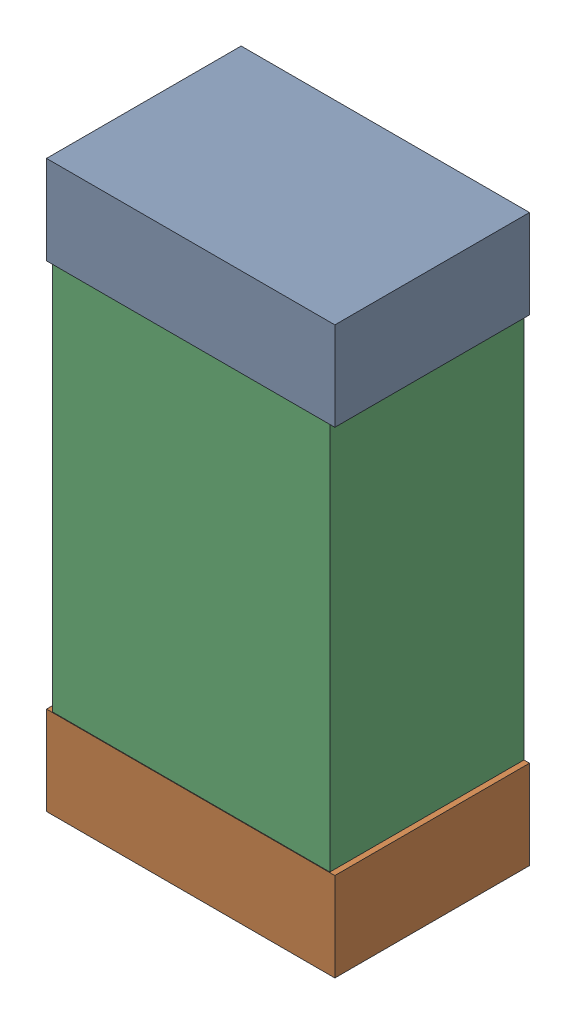
SolidWorks assembly C35, configuration Default. Lengths in mm.
Overall size (0.52 1.02 0.35).
6 component instances, 2 part files, 0 mates.
Components (placement in the parent):
- 870941120-1: 870941120 [Default] at (40.666 26.961 0) size (0.52 0.16 0.35)
  - Extruded_3-1: Extruded_3 [Default] at origin size (0.52 0.16 0.35)
- 870941120-2: 870941120 [Default] at (40.666 26.101 0) size (0.52 0.16 0.35)
  - Extruded_3-1: Extruded_3 [Default] at origin size (0.52 0.16 0.35)
- 870941280-1: 870941280 [Default] at (40.666 26.531 0) size (0.5 1 0.35)
  - Extruded_4-1: Extruded_4 [Default] at origin size (0.5 1 0.35)
